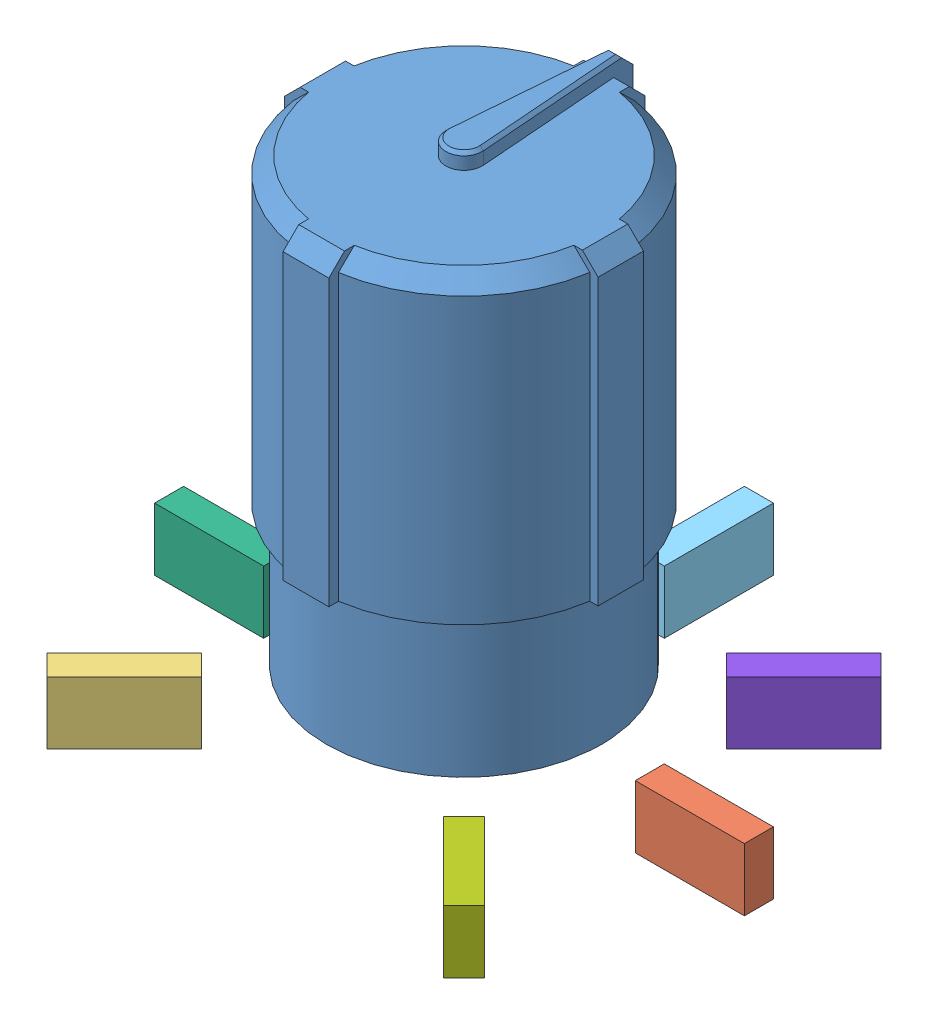
SolidWorks assembly Baugruppe3, configuration Standard. Lengths in mm.
Overall size (14.96 13.18 13.03).
9 component instances, 8 part files, 2 mates.
Components (placement in the parent):
- Small-Knob-1: Small-Knob [Standard] at (-4.6762 -0.786 11.6575) size (7.95 11.59 8.16)
- Small-Knob-Leds-1: Small-Knob-Leds [Standard] at (-4.6762 -5.9454 11.6575) size (14.96 1.59 13.03)
  - Small-Knob-Led-6-1: Small-Knob-Led-6 [Standard] at origin size (2.77 1.59 0.74)
  - Small-Knob-Led-1-1: Small-Knob-Led-1 [Standard] at origin size (2.48 1.59 2.48)
  - Small-Knob-Led-3-1: Small-Knob-Led-3 [Standard] at origin size (2.48 1.59 2.48)
  - Small-Knob-Led-4-1: Small-Knob-Led-4 [Standard] at origin size (0.74 1.59 2.77)
  - Small-Knob-Led-2-1: Small-Knob-Led-2 [Standard] at origin size (2.77 1.59 0.74)
  - Small-Knob-Led-7-1: Small-Knob-Led-7 [Standard] at origin size (2.48 1.59 2.48)
  - Small-Knob-Led-5-1: Small-Knob-Led-5 [Standard] at origin size (2.48 1.59 2.48)
Mates (geometry in assembly coordinates):
- Konzentrisch1: concentric: circle of Small-Knob-1; line of ? through (-4.6762 -4.3579 11.6575) axis (0 -1 0)
- Deckungsgleich1: coincident anti-aligned: plane of Small-Knob-1 through (-4.6762 -4.3579 11.6575) normal (0 -1 0); plane of ? through (-10.7738 -4.3579 11.6575) normal (0 1 0)
